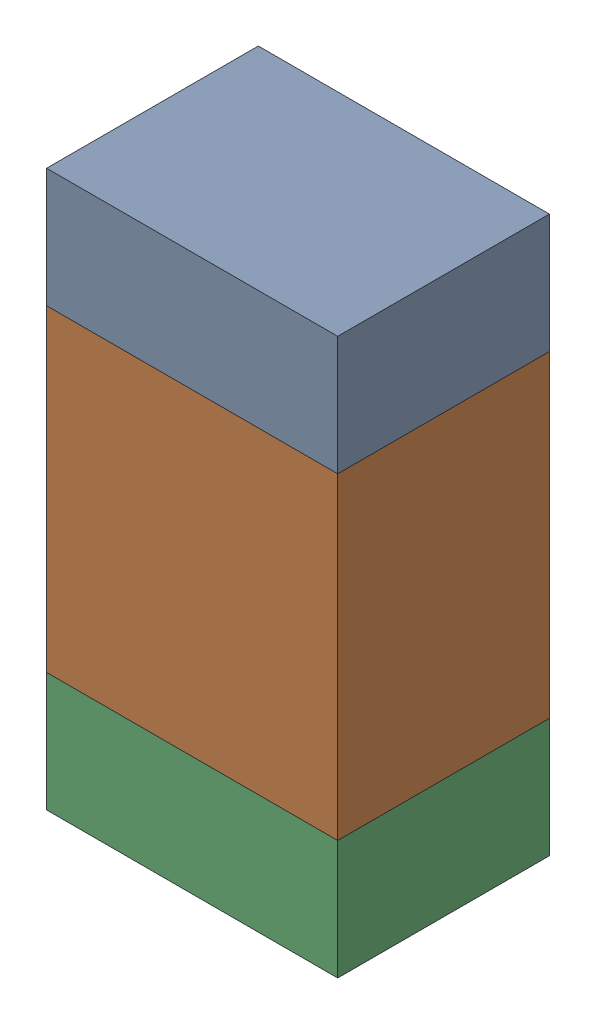
SolidWorks assembly R313_2PCB, configuration Default. Lengths in mm.
Overall size (0.55 1.05 0.4).
6 component instances, 2 part files, 0 mates.
Components (placement in the parent):
- 846483288-1: 846483288 [Default] at (126.9999 93.5124 -2.0638) size (0.55 0.22 0.4)
  - Extruded_12-1: Extruded_12 [Default] at origin size (0.55 0.22 0.4)
- 846483424-1: 846483424 [Default] at (126.9999 93.0999 -2.0638) size (0.55 0.6 0.4)
  - Extruded_13-1: Extruded_13 [Default] at origin size (0.55 0.6 0.4)
- 846483288-2: 846483288 [Default] at (126.9999 92.6874 -2.0638) size (0.55 0.22 0.4)
  - Extruded_12-1: Extruded_12 [Default] at origin size (0.55 0.22 0.4)
